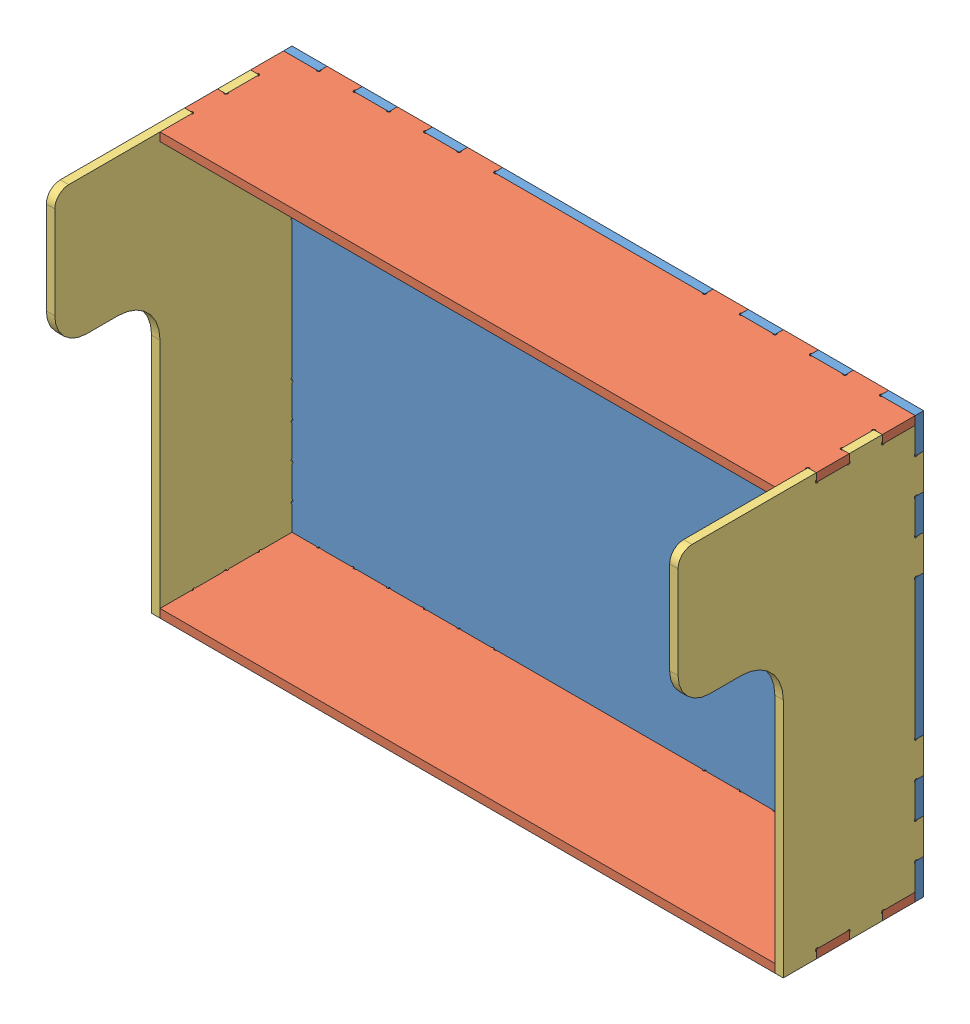
SolidWorks assembly ensamblecamamuypro, configuration Default. Lengths in mm.
Overall size (900 600 350).
5 component instances, 3 part files, 11 mates.
Components (placement in the parent):
- basecamamurpro-1: basecamamurpro [Default] at (250.9197 579.6751 731.2912) size (900 600 12)
- ladofinocamamuypro-1: ladofinocamamuypro [Default] at (346.2281 733.3063 848.1881) x (-1 0 0) z (0 -1 0) size (900 200 12)
- ladofinocamamuypro-2: ladofinocamamuypro [Default] at (243.1912 133.3063 848.1881) x (1 0 0) z (0 1 0) size (900 200 12)
- ladogruesobasecamamuypro-1: ladogruesobasecamamuypro [Default] at (-143.2903 431.3189 867.9489) x (0 1 0) z (-1 0 0) size (600 350 12)
- ladogruesobasecamamuypro-2: ladogruesobasecamamuypro [Default] at (744.7097 431.3189 867.9489) x (0 1 0) z (-1 0 0) size (600 350 12)
Mates (geometry in assembly coordinates):
- Coincident1: coincident aligned: line of basecamamurpro-1 through (-58.5688 721.3063 731.2912) axis (-1 0 0); line of ladofinocamamuypro-1 through (-55.2903 721.3063 731.2912) axis (-1 0 0)
- Coincident2: coincident anti-aligned: plane of basecamamurpro-1 through (-105.2903 733.3063 743.2912) normal (1 0 0); plane of ladofinocamamuypro-1 through (-105.2903 721.3063 740.0239) normal (-1 0 0)
- Coincident3: coincident anti-aligned: plane of basecamamurpro-1 through (-102.0119 721.3063 743.2912) normal (0 1 0); plane of ladofinocamamuypro-1 through (93.4905 721.3063 742.0912) normal (0 -1 0)
- Coincident4: coincident aligned: line of basecamamurpro-1 through (-102.0119 145.3063 731.2912) axis (1 0 0); line of ladofinocamamuypro-2 through (-105.2903 145.3063 731.2912) axis (1 0 0)
- Coincident5: coincident anti-aligned: line of basecamamurpro-1 through (-105.2903 133.3063 731.2912) axis (0 1 0); line of ladofinocamamuypro-2 through (-105.2903 145.3063 731.2912) axis (0 -1 0)
- Coincident6: coincident aligned: line of basecamamurpro-1 through (-143.2903 230.0278 731.2912) axis (0 -1 0); line of ladogruesobasecamamuypro-1 through (-143.2903 233.3063 731.2912) axis (0 -1 0)
- Coincident7: coincident anti-aligned: plane of basecamamurpro-1 through (-155.2903 183.3063 743.2912) normal (0 1 0); plane of ladogruesobasecamamuypro-1 through (-155.2903 183.3063 731.2912) normal (0 -1 0)
- Coincident8: coincident anti-aligned: plane of basecamamurpro-1 through (-143.2903 580.0278 743.2912) normal (-1 0 0); plane of ladogruesobasecamamuypro-1 through (-143.2903 144.1063 789.0912) normal (1 0 0)
- Coincident12: coincident anti-aligned: line of basecamamurpro-1 through (732.7097 286.5848 731.2912) axis (0 1 0); line of ladogruesobasecamamuypro-2 through (732.7097 333.3063 731.2912) axis (0 -1 0)
- Coincident13: coincident anti-aligned: plane of basecamamurpro-1 through (744.7097 583.3063 743.2912) normal (0 -1 0); plane of ladogruesobasecamamuypro-2 through (732.7097 583.3063 740.0128) normal (0 1 0)
- Coincident16: coincident anti-aligned: plane of basecamamurpro-1 through (732.7097 186.5848 743.2912) normal (1 0 0); plane of ladogruesobasecamamuypro-2 through (732.7097 144.1063 789.0912) normal (-1 0 0)
